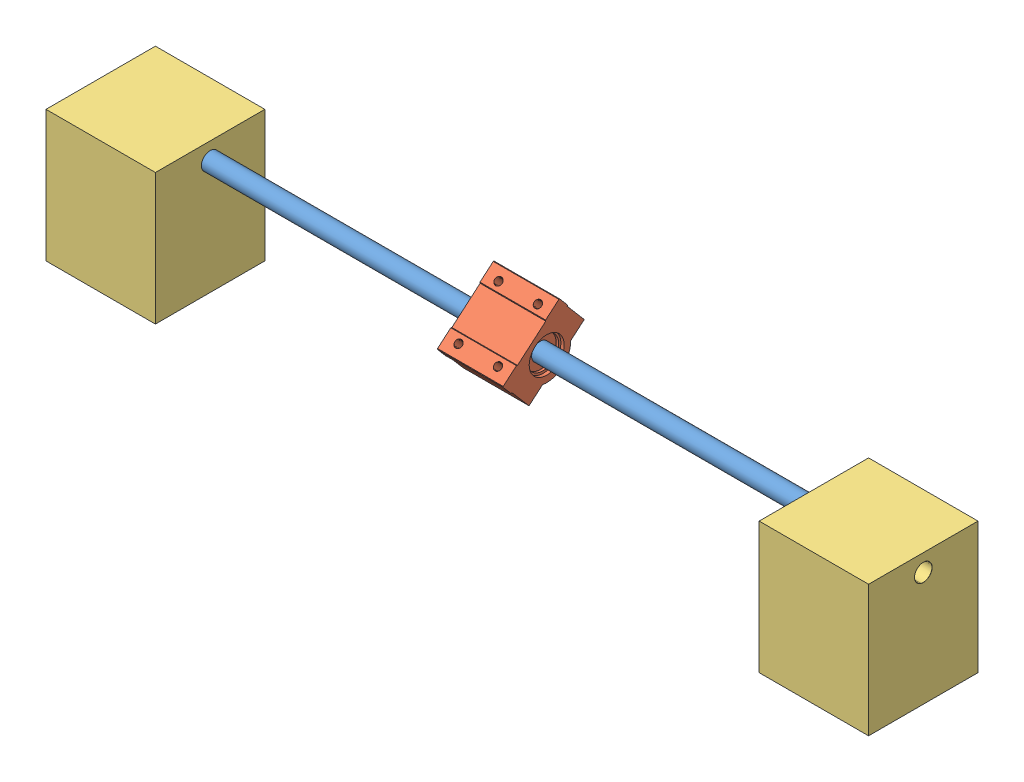
SolidWorks assembly Assem2, configuration Default. Lengths in mm.
Overall size (375.88 71.59 50).
4 component instances, 3 part files, 3 mates.
Components (placement in the parent):
- Default-1: Default [Default] at (-23.0861 13.9317 2.7172) size (300 8 8)
- L1750.008-1: L1750.008 [Default] at (-24.0631 13.9317 2.7172) x (0 0.649595 -0.760281) z (1 0 0) size (34 22 30)
- BEAM-1: BEAM [Default] at (138.0328 -38.2524 2.7172) size (50 60 50)
- BEAM-2: BEAM [Default] at (-187.8515 -38.2524 2.7172) size (50 60 50)
Mates (geometry in assembly coordinates):
- Concentric1: concentric anti-aligned: circle of Default-1; circle of L1750.008-1
- Concentric4: concentric anti-aligned: cylinder of Default-1 through (126.9139 13.9317 2.7172) axis (-1 0 0) radius 4; cylinder of BEAM-1 through (163.0328 13.9317 2.7172) axis (1 0 0) radius 4
- Concentric5: concentric anti-aligned: cylinder of Default-1 through (126.9139 13.9317 2.7172) axis (-1 0 0) radius 4; cylinder of BEAM-2 through (-162.8515 13.9317 2.7172) axis (1 0 0) radius 4
